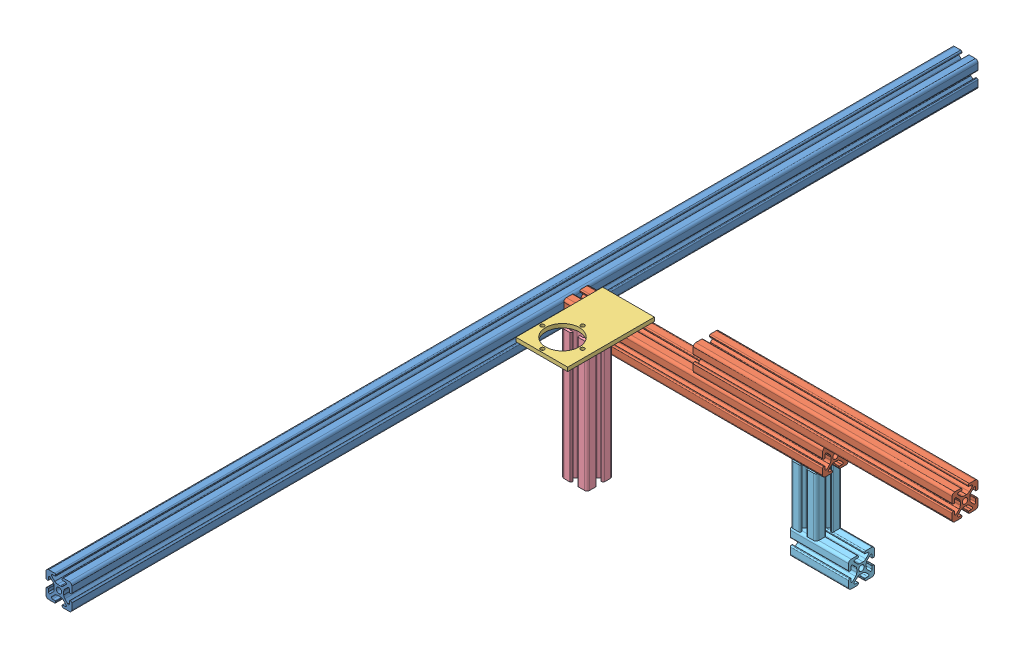
SolidWorks assembly CraneTilterFrame, configuration Default. Lengths in mm.
Overall size (320 120 700).
7 component instances, 5 part files, 21 mates.
Components (placement in the parent):
- PP4030Rollco20_20_400-1: PP4030Rollco20_20_400 [PP4030-50-Rollco] at origin size (20 20 700)
- PP4030RollcoHandle_200-1: PP4030RollcoHandle_200 [PP4030-50-Rollco] at (35 0 -365) x (0 0 1) z (-1 0 0) size (20 20 200)
- PP4030RollcoHandle_200-2: PP4030RollcoHandle_200 [PP4030-50-Rollco] at (135 20 -365) x (0 0 1) z (-1 0 0) size (20 20 200)
- BottomPlate-1: BottomPlate [Default] at (167.33 10 -271.1) x (0 0 -1) z (0 1 0) size (67 40 3)
- PP4030-100-Rollco-1: PP4030-100-Rollco [PP4030-50-Rollco] at (38 -15 -345) x (1 0 0) z (0 1 0) size (20 20 100)
- PP4030_TiltStopper-1: PP4030_TiltStopper [PP4030-50-Rollco] at (195 -35 -365) x (1 0 0) z (0 1 0) size (20 20 45)
- PP4030_TiltStopper-2: PP4030_TiltStopper [PP4030-50-Rollco] at (210 -65 -365) x (0 0 1) z (-1 0 0) size (20 20 45)
Mates (geometry in assembly coordinates):
- Coincident1: coincident anti-aligned: plane of PP4030Rollco20_20_400-1 through (10 -10 -675) normal (1 0 0); plane of PP4030RollcoHandle_200-1 through (10 -10 -355) normal (-1 0 0)
- Coincident2: coincident aligned: plane of PP4030Rollco20_20_400-1 through (-10 10 -675) normal (0 1 0); plane of PP4030RollcoHandle_200-1 through (210 10 -375) normal (0 1 0)
- Distance1: distance = 300 mm aligned: plane of PP4030RollcoHandle_200-1 through (210 -10 -375) normal (0 0 -1); plane of PP4030Rollco20_20_400-1 through (10 -10 -675) normal (0 0 -1)
- Coincident4: coincident aligned: plane of PP4030RollcoHandle_200-1 through (210 -10 -355) normal (0 0 1); plane of PP4030RollcoHandle_200-2 through (310 10 -355) normal (0 0 1)
- Coincident5: coincident anti-aligned: plane of PP4030RollcoHandle_200-1 through (210 10 -375) normal (0 1 0); plane of PP4030RollcoHandle_200-2 through (310 10 -375) normal (0 -1 0)
- Distance2: distance = 100 mm aligned: plane of PP4030RollcoHandle_200-2 through (310 10 -355) normal (1 0 0); plane of PP4030RollcoHandle_200-1 through (210 -10 -355) normal (1 0 0)
- Coincident7: coincident aligned: plane of PP4030Rollco20_20_400-1 through (0 0 0) normal (1 0 0)
- Coincident8: coincident aligned: plane of PP4030Rollco20_20_400-1 through (0 0 0) normal (0 0 1)
- Coincident9: coincident aligned: plane of PP4030Rollco20_20_400-1 through (0 0 0) normal (0 1 0)
- Coincident13: coincident aligned: plane of PP4030RollcoHandle_200-1 through (210 -10 -375) normal (0 0 -1); plane of BottomPlate-1 through (20 13 -375) normal (0 0 -1)
- Coincident14: coincident anti-aligned: plane of PP4030RollcoHandle_200-1 through (210 10 -375) normal (0 1 0); plane of BottomPlate-1 through (167.33 10 -271.1) normal (0 -1 0)
- Distance3: distance = 10 mm: line of PP4030Rollco20_20_400-1 through (10 -8 -675) axis (0 0 1); plane of BottomPlate-1 through (20 13 -308) normal (-1 0 0)
- Coincident16: coincident anti-aligned: plane of BottomPlate-1 through (167.33 10 -271.1) normal (0 -1 0); plane of PP4030-100-Rollco-1 through (48 10 -335) normal (0 1 0)
- Coincident17: coincident anti-aligned: plane of PP4030RollcoHandle_200-1 through (210 -10 -355) normal (0 0 1); plane of PP4030-100-Rollco-1 through (28 -90 -355) normal (0 0 -1)
- Distance4: distance = 8 mm aligned: plane of PP4030-100-Rollco-1 through (28 -90 -335) normal (-1 0 0); plane of BottomPlate-1 through (20 13 -308) normal (-1 0 0)
- Coincident18: coincident anti-aligned: plane of PP4030RollcoHandle_200-1 through (210 -10 -375) normal (0 -1 0); plane of PP4030_TiltStopper-1 through (205 -10 -355) normal (0 1 0)
- Coincident19: coincident aligned: plane of PP4030RollcoHandle_200-1 through (210 -10 -355) normal (0 0 1); plane of PP4030_TiltStopper-1 through (185 -55 -355) normal (0 0 1)
- Coincident21: coincident aligned: plane of PP4030_TiltStopper-1 through (185 -55 -355) normal (-1 0 0); plane of PP4030_TiltStopper-2 through (185 -75 -355) normal (-1 0 0)
- Coincident22: coincident aligned: plane of PP4030_TiltStopper-1 through (185 -55 -355) normal (0 0 1); plane of PP4030_TiltStopper-2 through (230 -75 -355) normal (0 0 1)
- Coincident23: coincident anti-aligned: plane of PP4030_TiltStopper-1 through (205 -55 -355) normal (0 -1 0); plane of PP4030_TiltStopper-2 through (230 -55 -375) normal (0 1 0)
- Distance6: distance = 5 mm aligned: plane of PP4030_TiltStopper-1 through (205 -55 -355) normal (1 0 0); plane of PP4030RollcoHandle_200-1 through (210 -10 -355) normal (1 0 0)
